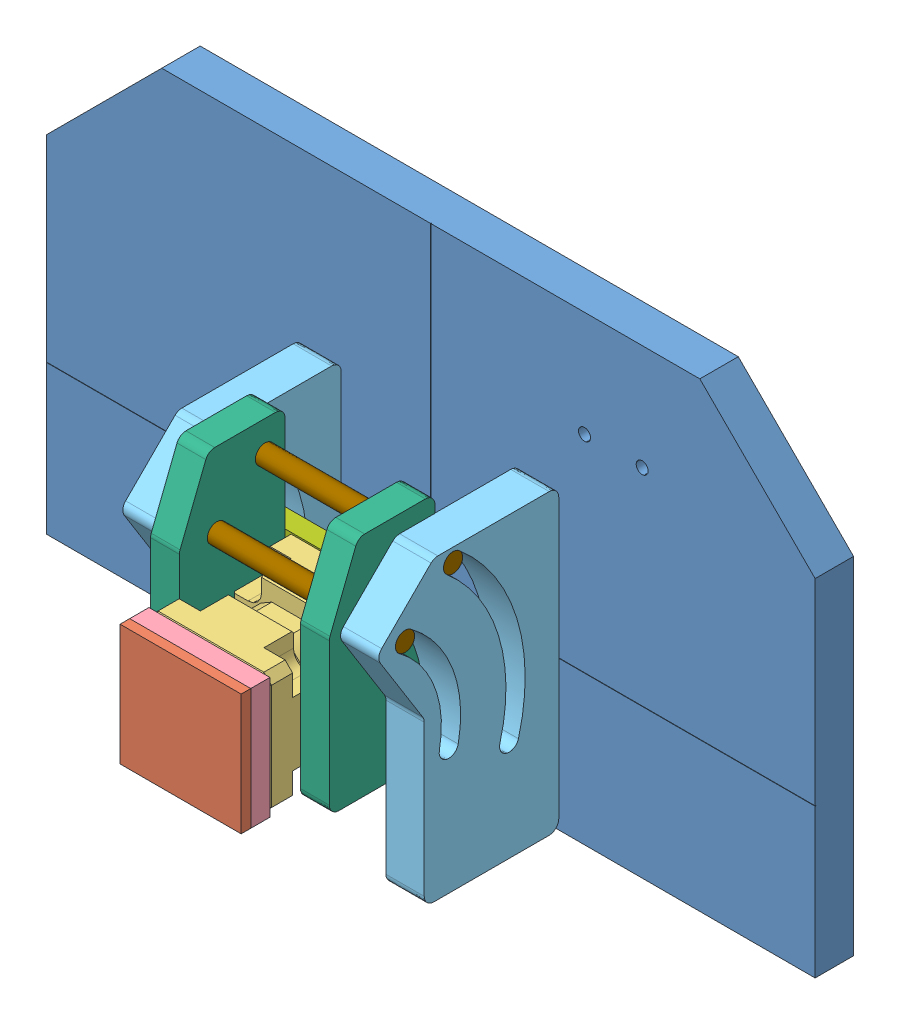
SolidWorks assembly Assembly, configuration Default. Lengths in mm.
Overall size (508 304.8 190.99).
19 component instances, 10 part files, 45 mates.
Components (placement in the parent):
- Infinity Plate-1: Infinity Plate [Default] at (215.3484 366.3522 346.8457) size (508 304.8 25.47)
- coupon filler-1: coupon filler [Default] at (228.3793 216.9768 531.4861) x (-1 0 0) z (0 1 0) size (80.01 6.35 80.01)
- Kister 3 Axis Load Cell (9367C)-1: Kister 3 Axis Load Cell (9367C) [Default] at (188.3693 256.9868 473.7861) x (-1 0 0) z (0 1 0) size (80 92.71 80)
- vaccum filler-1: vaccum filler [Default] at (228.3793 216.9768 518.7861) x (-1 0 0) z (0 1 0) size (80.01 12.7 80.01)
- 1_inch_d 1.625_inch_long hex bolt-1: 1_inch_d 1.625_inch_long hex bolt [Default] at (116.2282 336.3568 346.8457) x (0 0 -1) z (0.382349 0.924018 0) size (40.64 31.27 32.99) (hidden)
- 1_inch_d 1.625_inch_long hex bolt-2: 1_inch_d 1.625_inch_long hex bolt [Default] at (116.2282 177.6068 346.8457) x (0 0 -1) z (0.205767 0.978601 0) size (40.64 31.27 32.99) (hidden)
- Plate Attachment-1: Plate Attachment [Default] at (103.5282 355.4068 372.2457) x (0 0 -1) z (1 0 0) size (118.94 196.75 25.4)
- Base Attachment-1: Base Attachment [Default] at (228.3692 366.8368 428.7861) x (0 0 -1) z (1 0 0) size (69.85 149.86 19.05)
- Sensor Base-1: Sensor Base [Default] at (188.3642 256.9818 416.0861) x (-1 0 0) z (0 1 0) size (118.11 12.7 80.01)
- Screw Sensor-1: Screw Sensor [Default] at (218.3693 286.9868 412.2761) x (0.995144 0.098427 0) z (0.098427 -0.995144 0) size (10.41 29.21 10.41)
- Screw Sensor-2: Screw Sensor [Default] at (158.3592 226.9767 412.2761) x (0.995144 0.098427 0) z (0.098427 -0.995144 0) size (10.41 29.21 10.41)
- Screw Sensor-3: Screw Sensor [Default] at (218.3693 226.9767 412.2761) x (0.995144 0.098427 0) z (0.098427 -0.995144 0) size (10.41 29.21 10.41)
- Screw Sensor-4: Screw Sensor [Default] at (158.3592 286.9868 412.2761) x (0.995144 0.098427 0) z (0.098427 -0.995144 0) size (10.41 29.21 10.41)
- Base Attachment-2: Base Attachment [Default] at (129.3092 366.8368 428.7861) x (0 0 -1) z (1 0 0) size (69.85 149.86 19.05)
- Plate Attachment-2: Plate Attachment [Default] at (247.2922 355.4068 372.2457) x (0 0 -1) z (1 0 0) size (118.94 196.75 25.4)
- 1_inch_d 1.625_inch_long hex bolt-3: 1_inch_d 1.625_inch_long hex bolt [Default] at (259.9922 336.3568 346.8457) x (0 0 -1) z (0.99969 0.024893 0) size (40.64 31.27 32.99) (hidden)
- 1_inch_d 1.625_inch_long hex bolt-4: 1_inch_d 1.625_inch_long hex bolt [Default] at (259.9922 177.6068 346.8457) x (0 0 -1) z (0.205767 0.978601 0) size (40.64 31.27 32.99) (hidden)
- dOWEL-1: dOWEL [Default] at (103.5282 346.5168 442.0957) x (1 0 0) z (0 0.585166 0.810913) size (169.16 12.7 12.7)
- dOWEL-2: dOWEL [Default] at (103.5282 317.3068 473.8457) x (1 0 0) z (0 -0.69333 -0.72062) size (169.16 12.7 12.7)
Mates (geometry in assembly coordinates):
- Coincident1: coincident anti-aligned: plane of Kister 3 Axis Load Cell (9367C)-1 through (188.3693 256.9868 428.7861) normal (0 0 -1); plane of Sensor Base-1 through (188.3642 256.9818 428.7861) normal (0 0 1)
- Coincident2: coincident aligned: plane of Kister 3 Axis Load Cell (9367C)-1 through (223.3693 296.9868 428.7861) normal (0 1 0); plane of Sensor Base-1 through (247.4192 296.9868 428.7861) normal (0 1 0)
- Coincident3: coincident anti-aligned: plane of Kister 3 Axis Load Cell (9367C)-1 through (188.3693 256.9868 518.7861) normal (0 0 1); plane of vaccum filler-1 through (228.3793 216.9768 518.7861) normal (0 0 -1)
- Coincident4: coincident aligned: plane of Kister 3 Axis Load Cell (9367C)-1 through (223.3693 296.9868 518.7861) normal (0 1 0); plane of vaccum filler-1 through (228.3793 296.9868 531.4861) normal (0 1 0)
- Coincident5: coincident aligned: plane of Kister 3 Axis Load Cell (9367C)-1 through (148.3693 291.9868 518.7861) normal (-1 0 0); plane of vaccum filler-1 through (148.3693 216.9768 531.4861) normal (-1 0 0)
- Coincident6: coincident anti-aligned: plane of coupon filler-1 through (228.3793 216.9768 531.4861) normal (0 0 -1); plane of vaccum filler-1 through (228.3793 216.9768 531.4861) normal (0 0 1)
- Coincident7: coincident aligned: plane of coupon filler-1 through (228.3793 296.9868 537.8361) normal (0 1 0); plane of vaccum filler-1 through (228.3793 296.9868 531.4861) normal (0 1 0)
- Coincident8: coincident aligned: plane of coupon filler-1 through (148.3693 216.9768 537.8361) normal (-1 0 0); plane of vaccum filler-1 through (148.3693 216.9768 531.4861) normal (-1 0 0)
- Coincident9: coincident anti-aligned: plane of Base Attachment-1 through (247.4192 366.8368 428.7861) normal (0 0 -1); plane of Sensor Base-1 through (188.3642 256.9818 428.7861) normal (0 0 1)
- Concentric1: concentric aligned: cylinder of Base Attachment-1 through (237.8942 284.2868 444.0261) axis (0 0 -1) radius 7.9375; cylinder of Sensor Base-1 through (237.8942 284.2868 428.7861) axis (0 0 -1) radius 7.9375
- Concentric2: concentric aligned: cylinder of Base Attachment-1 through (237.8942 229.6768 444.0261) axis (0 0 -1) radius 7.9375; cylinder of Sensor Base-1 through (237.8942 229.6768 428.7861) axis (0 0 -1) radius 7.9375
- Concentric3: concentric anti-aligned: cylinder of Kister 3 Axis Load Cell (9367C)-1 through (218.3693 286.9868 428.7861) axis (0 0 1) radius 4.188; cylinder of Sensor Base-1 through (218.3693 286.9868 428.7861) axis (0 0 -1) radius 4.445
- Concentric4: concentric aligned: circle of Sensor Base-1; cylinder of Screw Sensor-1 through (218.3693 286.9868 441.4861) axis (0 0 -1) radius 3.937
- Concentric5: concentric aligned: cylinder of Sensor Base-1 through (158.3592 286.9868 428.7861) axis (0 0 -1) radius 4.445; cylinder of Screw Sensor-4 through (158.3592 286.9868 441.4861) axis (0 0 -1) radius 3.937
- Concentric6: concentric aligned: cylinder of Sensor Base-1 through (218.3693 226.9767 428.7861) axis (0 0 -1) radius 4.445; cylinder of Screw Sensor-3 through (218.3693 226.9767 441.4861) axis (0 0 -1) radius 3.937
- Concentric7: concentric aligned: cylinder of Sensor Base-1 through (158.3592 226.9767 428.7861) axis (0 0 -1) radius 4.445; cylinder of Screw Sensor-2 through (158.3592 226.9767 441.4861) axis (0 0 -1) radius 3.937
- Coincident11: coincident anti-aligned: plane of Sensor Base-1 through (188.3642 256.9818 416.0861) normal (0 0 -1); plane of Screw Sensor-3 through (218.3693 226.9767 416.0861) normal (0 0 1)
- Coincident12: coincident anti-aligned: plane of Sensor Base-1 through (188.3642 256.9818 416.0861) normal (0 0 -1); plane of Screw Sensor-1 through (218.3693 286.9868 416.0861) normal (0 0 1)
- Coincident13: coincident anti-aligned: plane of Sensor Base-1 through (188.3642 256.9818 416.0861) normal (0 0 -1); plane of Screw Sensor-4 through (158.3592 286.9868 416.0861) normal (0 0 1)
- Coincident14: coincident anti-aligned: plane of Sensor Base-1 through (188.3642 256.9818 416.0861) normal (0 0 -1); plane of Screw Sensor-2 through (158.3592 226.9767 416.0861) normal (0 0 1)
- Coincident15: coincident anti-aligned: plane of Infinity Plate-1 through (215.3484 366.3522 372.2457) normal (0 0 1); plane of Plate Attachment-1 through (128.9282 355.4068 372.2457) normal (0 0 -1)
- Concentric8: concentric aligned: cylinder of Infinity Plate-1 through (116.2282 336.3568 372.3116) axis (0 0 -1) radius 9.525; cylinder of Plate Attachment-1 through (116.2282 336.3568 381.1357) axis (0 0 -1) radius 9.525
- Concentric10: concentric aligned: cylinder of Infinity Plate-1 through (116.2282 336.3568 372.3116) axis (0 0 -1) radius 9.525; cylinder of 1_inch_d 1.625_inch_long hex bolt-1 through (116.2282 336.3568 378.5957) axis (0 0 -1) radius 9.525
- Concentric11: concentric aligned: cylinder of Infinity Plate-1 through (116.2282 177.6068 372.3116) axis (0 0 -1) radius 9.525; cylinder of 1_inch_d 1.625_inch_long hex bolt-2 through (116.2282 177.6068 378.5957) axis (0 0 -1) radius 9.525
- Coincident16: coincident anti-aligned: plane of Infinity Plate-1 through (215.3484 366.3522 346.8457) normal (0 0 -1); plane of 1_inch_d 1.625_inch_long hex bolt-1 through (116.2282 336.3568 346.8457) normal (0 0 1)
- Coincident17: coincident anti-aligned: plane of Infinity Plate-1 through (215.3484 366.3522 346.8457) normal (0 0 -1); plane of 1_inch_d 1.625_inch_long hex bolt-2 through (116.2282 177.6068 346.8457) normal (0 0 1)
- Coincident18: coincident anti-aligned: plane of Infinity Plate-1 through (215.3484 366.3522 372.2457) normal (0 0 1); plane of Plate Attachment-2 through (272.6922 355.4068 372.2457) normal (0 0 -1)
- Concentric13: concentric aligned: cylinder of Infinity Plate-1 through (259.9922 336.3568 372.3116) axis (0 0 -1) radius 9.525; cylinder of Plate Attachment-2 through (259.9922 336.3568 381.1357) axis (0 0 -1) radius 9.525
- Concentric15: concentric aligned: cylinder of Infinity Plate-1 through (259.9922 177.6068 372.3116) axis (0 0 -1) radius 9.525; cylinder of 1_inch_d 1.625_inch_long hex bolt-4 through (259.9922 177.6068 378.5957) axis (0 0 -1) radius 9.525
- Concentric16: concentric aligned: cylinder of Infinity Plate-1 through (259.9922 336.3568 372.3116) axis (0 0 -1) radius 9.525; cylinder of 1_inch_d 1.625_inch_long hex bolt-3 through (259.9922 336.3568 378.5957) axis (0 0 -1) radius 9.525
- Coincident19: coincident anti-aligned: plane of Infinity Plate-1 through (215.3484 366.3522 346.8457) normal (0 0 -1); plane of 1_inch_d 1.625_inch_long hex bolt-3 through (259.9922 336.3568 346.8457) normal (0 0 1)
- Coincident20: coincident anti-aligned: plane of Infinity Plate-1 through (215.3484 366.3522 346.8457) normal (0 0 -1); plane of 1_inch_d 1.625_inch_long hex bolt-4 through (259.9922 177.6068 346.8457) normal (0 0 1)
- Coincident21: coincident anti-aligned: plane of Sensor Base-1 through (188.3642 256.9818 428.7861) normal (0 0 1); plane of Base Attachment-2 through (148.3592 366.8368 428.7861) normal (0 0 -1)
- Concentric17: concentric aligned: cylinder of Sensor Base-1 through (138.8342 229.6768 428.7861) axis (0 0 -1) radius 7.9375; cylinder of Base Attachment-2 through (138.8342 229.6768 444.0261) axis (0 0 -1) radius 7.9375
- Concentric18: concentric aligned: cylinder of Sensor Base-1 through (138.8342 284.2868 428.7861) axis (0 0 -1) radius 7.9375; cylinder of Base Attachment-2 through (138.8342 284.2868 444.0261) axis (0 0 -1) radius 7.9375
- Concentric19: concentric anti-aligned: cylinder of Base Attachment-2 through (129.3092 317.3068 473.8457) axis (1 0 0) radius 6.35; cylinder of dOWEL-2 through (272.6922 317.3068 473.8457) axis (-1 0 0) radius 6.35
- Tangent1: tangent aligned: cylinder of Plate Attachment-2 through (247.2922 257.0842 518.2957) axis (1 0 0) radius 81.2002; cylinder of dOWEL-2 through (272.6922 317.3068 473.8457) axis (-1 0 0) radius 6.35
- Coincident22: coincident aligned: plane of Plate Attachment-2 through (272.6922 355.4068 372.2457) normal (1 0 0); plane of dOWEL-2 through (272.6922 317.3068 473.8457) normal (1 0 0)
- Concentric21: concentric anti-aligned: cylinder of Base Attachment-2 through (129.3092 346.5168 442.0957) axis (1 0 0) radius 6.35; cylinder of dOWEL-1 through (272.6922 346.5168 442.0957) axis (-1 0 0) radius 6.35
- Coincident23: coincident aligned: plane of Plate Attachment-2 through (272.6922 355.4068 372.2457) normal (1 0 0); plane of dOWEL-1 through (272.6922 346.5168 442.0957) normal (1 0 0)
- Tangent3: tangent aligned: cylinder of Plate Attachment-2 through (247.2922 257.0842 518.2957) axis (1 0 0) radius 123.8431; cylinder of dOWEL-1 through (272.6922 346.5168 442.0957) axis (-1 0 0) radius 6.35
- Parallel4: parallel aligned: plane of Infinity Plate-1 through (442.1102 158.5568 372.2457) normal (1 0 0); plane of Plate Attachment-2 through (272.6922 355.4068 372.2457) normal (1 0 0)
- Parallel5: parallel aligned: plane of Infinity Plate-1 through (-65.8898 387.1568 372.2457) normal (-1 0 0); plane of Plate Attachment-1 through (103.5282 355.4068 372.2457) normal (-1 0 0)
- Distance1: distance = 0.127 mm anti-aligned: plane of Base Attachment-1 through (247.4192 366.8368 428.7861) normal (1 0 0); plane of Plate Attachment-2 through (247.2922 355.4068 372.2457) normal (-1 0 0)
- Slot1: slot anti-aligned: cylinder of dOWEL-2 through (272.6922 317.3068 473.8457) axis (-1 0 0) radius 6.35; cylinder of Plate Attachment-2 through (247.2922 257.0842 518.2957) axis (1 0 0) radius 81.2002; cylinder of Plate Attachment-2 through (247.2922 242.25 444.9302) axis (1 0 0) radius 6.35
